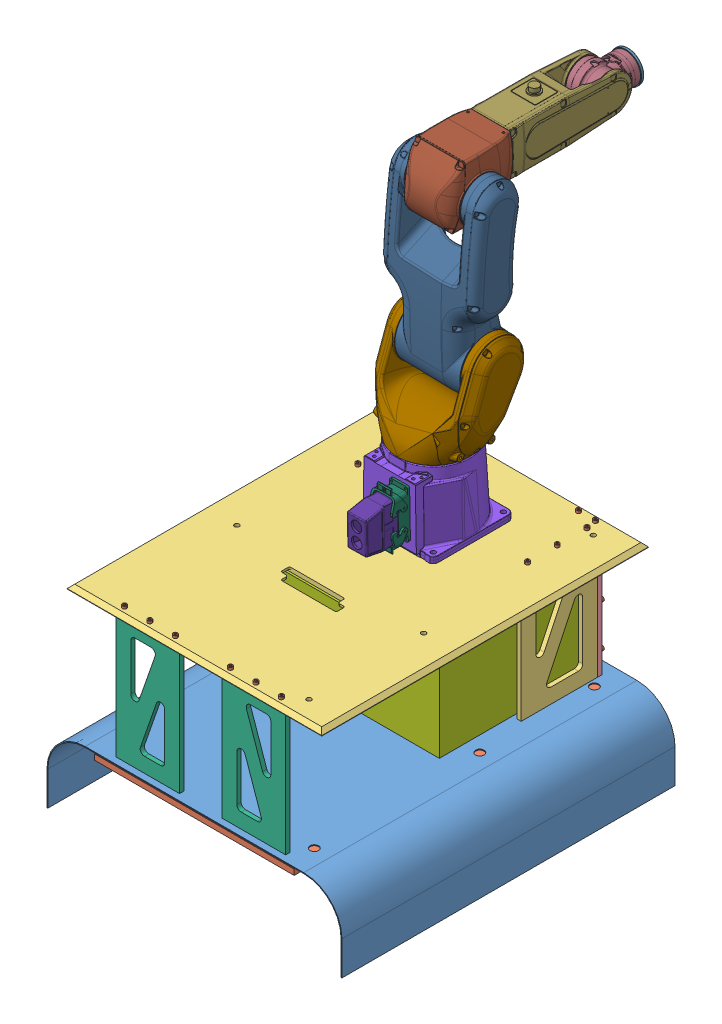
SolidWorks assembly Sistema - Copy, configuration Default. Lengths in mm.
Overall size (695 1239.93 1029.04).
63 component instances, 21 part files, 140 mates.
Components (placement in the parent):
- Curva-1: Curva [Default] at (251.6996 545.3448 205.6123) size (695 170 785)
- Placa Preta-1: Placa Preta [Default] at (486.6996 528.3448 990.6123) x (0 0 -1) z (1 0 0) size (785 15 470)
- L1-1: L1 [Default] at (456.6996 831.4223 235.6123) x (-1 0 0) z (0 0 1) size (60 300 190)
  - PLACA L2-1: PLACA L2 [Default] at (0 286.0775 10) x (0 0 1) z (0 1 0) size (180 10 300)
  - PLACA L1de-1: PLACA L1de [Default] at (0 -13.9225 0) size (60 300 10)
- L2-1: L2 [Default] at (108.7914 900.0363 -121.8565) x (-1 0 0) z (0 0 1) size (60 300 190)
  - PLACA L1d-1: PLACA L1d [Default] at (2.0918 54.6914 357.4688) size (60 300 10)
  - PLACA L2-1: PLACA L2 [Default] at (52.0918 354.6914 367.4688) x (0 0 1) z (0 1 0) size (180 10 300)
- PLACA B-1: PLACA B [Default] at (51.6996 545.3448 965.6123) x (1 0 0) z (0 -1 0) size (150 10 300)
- PLACA B-2: PLACA B [Default] at (451.6996 545.3448 975.6123) x (-1 0 0) z (0 -1 0) size (150 10 300)
- Contro-1: Contro [Default] at (438.6996 548.3448 255.6123) x (-1 0 0) z (0 0 -1) size (370 255 365) (hidden)
- Fanuc - LR Mate-200iD-1: Fanuc - LR Mate-200iD [Default] at (251.6996 856.3448 427.6123) x (0 0 -1) z (1 0 0) size (710.9 759.93 375.98)
  - J1BASE_UNIT-1: J1BASE_UNIT [Default] x (1 0 0) z (0 1 0) size (198 190.35 169.02)
  - J2BASE_UNIT-1: J2BASE_UNIT [Default] at (0 330 0) x (1 0 0) z (0 1 0) size (376.24 375.98 375.98)
  - J2ARM_UNIT-1: J2ARM_UNIT [Default] at (50 330 0) x (1 0 0) z (0 1 0) size (147.39 227.01 447.1)
  - J3HOUSING_UNIT-1: J3HOUSING_UNIT [Default] at (50 660 0) x (1 0 0) z (0 1 0) size (168.21 161.55 138.75)
  - J3ARM_UNIT-1: J3ARM_UNIT [Default] at (48.4 695.0266 0) x (1 0 0) z (0 1 0) size (328.04 104.81 113.9)
  - WRIST_UNIT-1: WRIST_UNIT [Default] at (383.4 695.0266 0) x (1 0 0) z (0 1 0) size (122.73 70.75 85.53)
  - J6RB_COVER-1: J6RB_COVER [Default] at (458.9 695.0266 0) x (0 -1 0) z (-1 0 0) size (74 74 15.5)
  - Harting HAN16B Housing-1: Harting HAN16B Housing [Default] at (-121.8 87.2194 28.1121) x (0 0.999848 -0.017452) z (0 0.017452 0.999848) size (131.63 46.6 57)
  - Harting DD72 Male Insert-1: Harting DD72 Male Insert [Default] at (-121.8 86.9777 28.6164) x (0 -0.999848 0.017452) z (0 0.017452 0.999848) size (84.5 35.16 34)
  - HArting HAN16B Hood-1: HArting HAN16B Hood [Default] at (-142.1 86.9695 28.1151) x (0 -0.999848 0.017452) z (0 -0.017452 -0.999848) size (93.56 76.01 57.01)
  - Harting DD72 Female Insert-1: Harting DD72 Female Insert [Default] at (-142.1 87.0381 28.1569) x (0 0.999848 -0.01745) z (0 0.01745 0.999848) size (84.5 36 34)
  - Fanuc LR-Mate 200iD Bottom Cover Plate-1: Fanuc LR-Mate 200iD Bottom Cover Plate [Default] at (-95.289 2 99.0244) x (0 0 -1) z (-1 0 0) size (165.51 3 180.93)
- socket head cap screw_iso-1: socket head cap screw_iso [ISO 4762 M6 x 20 - 20N] at (451.6996 595.3448 229.6123) x (0 0 1) z (-1 0 0) size (26 10 10)
- socket head cap screw_iso-2: socket head cap screw_iso [ISO 4762 M6 x 20 - 20N] at (451.6996 695.3448 229.6123) x (0 0 1) z (-1 0 0) size (26 10 10)
- socket head cap screw_iso-3: socket head cap screw_iso [ISO 4762 M6 x 20 - 20N] at (451.6996 795.3448 229.6123) x (0 0 1) z (-1 0 0) size (26 10 10)
- socket head cap screw_iso-4: socket head cap screw_iso [ISO 4762 M6 x 20 - 20N] at (51.6996 595.3448 229.6123) x (0 0 1) z (-1 0 0) size (26 10 10)
- socket head cap screw_iso-5: socket head cap screw_iso [ISO 4762 M6 x 20 - 20N] at (51.6996 695.3448 229.6123) x (0 0 1) z (-1 0 0) size (26 10 10)
- socket head cap screw_iso-6: socket head cap screw_iso [ISO 4762 M6 x 20 - 20N] at (51.6996 795.3448 229.6123) x (0 0 1) z (-1 0 0) size (26 10 10)
- socket head cap screw_iso-7: socket head cap screw_iso [ISO 4762 M6 x 30 - 30N] at (436.6996 522.3448 970.6123) x (0 1 0) z (0 0 1) size (36 10 10)
- socket head cap screw_iso-8: socket head cap screw_iso [ISO 4762 M6 x 30 - 30N] at (376.6996 522.3448 970.6123) x (0 1 0) z (0 0 1) size (36 10 10)
- socket head cap screw_iso-9: socket head cap screw_iso [ISO 4762 M6 x 30 - 30N] at (316.6996 522.3448 970.6123) x (0 1 0) z (0 0 1) size (36 10 10)
- socket head cap screw_iso-10: socket head cap screw_iso [ISO 4762 M6 x 30 - 30N] at (186.6996 522.3448 970.6123) x (0 1 0) z (0 0 1) size (36 10 10)
- socket head cap screw_iso-11: socket head cap screw_iso [ISO 4762 M6 x 30 - 30N] at (126.6996 522.3448 970.6123) x (0 1 0) z (0 0 1) size (36 10 10)
- socket head cap screw_iso-12: socket head cap screw_iso [ISO 4762 M6 x 30 - 30N] at (66.6996 522.3448 970.6123) x (0 1 0) z (0 0 1) size (36 10 10)
- socket head cap screw_iso-13: socket head cap screw_iso [ISO 4762 M6 x 30 - 30N] at (51.6996 522.3448 405.6123) x (0 1 0) z (0 0 1) size (36 10 10)
- socket head cap screw_iso-14: socket head cap screw_iso [ISO 4762 M6 x 30 - 30N] at (51.6996 522.3448 335.6123) x (0 1 0) z (0 0 1) size (36 10 10)
- socket head cap screw_iso-15: socket head cap screw_iso [ISO 4762 M6 x 30 - 30N] at (51.6996 522.3448 265.6123) x (0 1 0) z (0 0 1) size (36 10 10)
- socket head cap screw_iso-16: socket head cap screw_iso [ISO 4762 M6 x 30 - 30N] at (96.6996 522.3448 240.6123) x (0 1 0) z (0 0 1) size (36 10 10)
- socket head cap screw_iso-17: socket head cap screw_iso [ISO 4762 M6 x 30 - 30N] at (56.6996 522.3448 240.6123) x (0 1 0) z (0 0 1) size (36 10 10)
- socket head cap screw_iso-19: socket head cap screw_iso [ISO 4762 M6 x 30 - 30N] at (451.6996 522.3448 335.6123) x (0 1 0) z (-0.781824 0 0.623499) size (36 10 10)
- socket head cap screw_iso-20: socket head cap screw_iso [ISO 4762 M6 x 30 - 30N] at (451.6996 522.3448 265.6123) x (0 1 0) z (0 0 1) size (36 10 10)
- socket head cap screw_iso-21: socket head cap screw_iso [ISO 4762 M6 x 30 - 30N] at (446.6996 522.3448 240.6123) x (0 1 0) z (0 0 1) size (36 10 10)
- socket head cap screw_iso-22: socket head cap screw_iso [ISO 4762 M6 x 30 - 30N] at (406.6996 522.3448 240.6123) x (0 1 0) z (0 0 1) size (36 10 10)
- socket head cap screw_iso-25: socket head cap screw_iso [ISO 4762 M6 x 30 - 30N] at (451.6996 522.3448 405.6123) x (0 1 0) z (0 0 1) size (36 10 10)
- Placa Cima Simples-1: Placa Cima Simples [Default] at (-48.3004 845.3448 220.6123) x (0 0 1) z (-1 0 0) size (770 34 600)
- socket head cap screw_iso-27: socket head cap screw_iso [ISO 4762 M6 x 20 - 20N] at (436.6996 861.3448 970.6623) x (0 -1 0) z (0 0 1) size (26 10 10)
- socket head cap screw_iso-28: socket head cap screw_iso [ISO 4762 M6 x 20 - 20N] at (376.6996 861.3448 970.6623) x (0 -1 0) z (0 0 1) size (26 10 10)
- socket head cap screw_iso-29: socket head cap screw_iso [ISO 4762 M6 x 20 - 20N] at (316.6996 861.3448 970.5623) x (0 -1 0) z (0 0 1) size (26 10 10)
- socket head cap screw_iso-30: socket head cap screw_iso [ISO 4762 M6 x 20 - 20N] at (126.6996 861.3448 970.6623) x (0 -1 0) z (0 0 1) size (26 10 10)
- socket head cap screw_iso-31: socket head cap screw_iso [ISO 4762 M6 x 20 - 20N] at (66.6996 861.3448 970.6623) x (0 -1 0) z (0 0 1) size (26 10 10)
- socket head cap screw_iso-32: socket head cap screw_iso [ISO 4762 M6 x 20 - 20N] at (186.6996 861.3448 970.6623) x (0 -1 0) z (0 0 1) size (26 10 10)
- socket head cap screw_iso-34: socket head cap screw_iso [ISO 4762 M6 x 20 - 20N] at (451.6996 861.3448 405.6623) x (0 -1 0) z (0 0 1) size (26 10 10)
- socket head cap screw_iso-35: socket head cap screw_iso [ISO 4762 M6 x 20 - 20N] at (451.6996 861.3448 335.6623) x (0 -1 0) z (0 0 1) size (26 10 10)
- socket head cap screw_iso-36: socket head cap screw_iso [ISO 4762 M6 x 20 - 20N] at (451.6996 861.3448 265.6623) x (0 -1 0) z (0 0 1) size (26 10 10)
- socket head cap screw_iso-37: socket head cap screw_iso [ISO 4762 M6 x 20 - 20N] at (446.6996 861.3448 240.6623) x (0 -1 0) z (0 0 1) size (26 10 10)
- socket head cap screw_iso-38: socket head cap screw_iso [ISO 4762 M6 x 20 - 20N] at (406.6996 861.3448 240.6623) x (0 -1 0) z (0 0 1) size (26 10 10)
- socket head cap screw_iso-39: socket head cap screw_iso [ISO 4762 M6 x 20 - 20N] at (56.6996 861.3448 240.5623) x (0 -1 0) z (0 0 1) size (26 10 10)
- socket head cap screw_iso-40: socket head cap screw_iso [ISO 4762 M6 x 20 - 20N] at (96.6996 861.3448 240.5623) x (0 -1 0) z (0 0 1) size (26 10 10)
- socket head cap screw_iso-41: socket head cap screw_iso [ISO 4762 M6 x 20 - 20N] at (51.6996 861.3448 265.5623) x (0 -1 0) z (0 0 1) size (26 10 10)
- socket head cap screw_iso-42: socket head cap screw_iso [ISO 4762 M6 x 20 - 20N] at (51.6996 861.3448 405.5623) x (0 -1 0) z (0 0 1) size (26 10 10)
- socket head cap screw_iso-43: socket head cap screw_iso [ISO 4762 M6 x 20 - 20N] at (51.6996 861.3448 335.5623) x (0 -1 0) z (0 0 1) size (26 10 10)
Mates (geometry in assembly coordinates):
- Coincident1: coincident anti-aligned: plane of Curva-1 through (-5.8004 543.3448 205.6123) normal (0 -1 0); plane of Placa Preta-1 through (486.6996 543.3448 990.6123) normal (0 1 0)
- Parallel1: parallel anti-aligned: plane of Curva-1 through (599.1996 455.3448 205.6123) normal (1 0 0); plane of Placa Cima Simples-1 through (-48.3004 855.3448 220.6123) normal (-1 0 0)
- Distance1: distance = 300 mm: plane of Curva-1 through (-5.8004 545.3448 205.6123) normal (0 1 0); plane of Placa Cima Simples-1 through (-48.3004 845.3448 220.6123) normal (0 -1 0)
- Coincident4: coincident aligned: plane of Curva-1 through (251.6996 545.3448 205.6123) normal (-1 0 0); plane of Placa Preta-1 through (251.6996 528.3448 990.6123) normal (-1 0 0)
- Coincident25: coincident aligned: plane of Curva-1 through (-95.8004 375.3448 990.6123) normal (0 0 1); plane of Placa Preta-1 through (486.6996 543.3448 990.6123) normal (0 0 1)
- Coincident6: coincident anti-aligned: plane of Curva-1 through (-5.8004 545.3448 205.6123) normal (0 1 0); plane of L1-1/PLACA L2-1 through (446.6996 545.3448 245.6123) normal (0 -1 0)
- Distance2: distance = 30 mm aligned: plane of Placa Preta-1 through (486.6996 543.3448 205.6123) normal (0 0 -1); plane of L1-1/PLACA L1de-1 through (456.6996 845.3448 235.6123) normal (0 0 -1)
- Distance3: distance = 30 mm aligned: plane of L1-1/PLACA L2-1 through (456.6996 545.3448 245.6123) normal (1 0 0); plane of Placa Preta-1 through (486.6996 543.3448 990.6123) normal (1 0 0)
- Coincident9: coincident aligned: plane of L1-1/PLACA L1de-1 through (456.6996 845.3448 235.6123) normal (0 0 -1); plane of L2-1/PLACA L1d-1 through (106.6996 845.3448 235.6123) normal (0 0 -1)
- Coincident10: coincident anti-aligned: plane of Curva-1 through (-5.8004 545.3448 205.6123) normal (0 1 0); plane of L2-1/PLACA L2-1 through (46.6996 545.3448 245.6123) normal (0 -1 0)
- Distance4: distance = 30 mm aligned: plane of L2-1/PLACA L2-1 through (46.6996 545.3448 245.6123) normal (-1 0 0); plane of Placa Preta-1 through (16.6996 543.3448 990.6123) normal (-1 0 0)
- Coincident15: coincident anti-aligned: plane of Curva-1 through (251.6996 545.3448 205.6123) normal (1 0 0); plane of Placa Cima Simples-1 through (251.6996 845.3448 220.6123) normal (-1 0 0)
- Distance5: distance = 370 mm: plane of Placa Cima Simples-1 through (-48.3004 845.3448 605.6123) normal (0 0 -1); plane of L2-1/PLACA L1d-1 through (106.6996 845.3448 235.6123) normal (0 0 -1)
- Coincident16: coincident anti-aligned: plane of Curva-1 through (-5.8004 545.3448 205.6123) normal (0 1 0); plane of PLACA B-1 through (51.6996 545.3448 975.6123) normal (0 -1 0)
- Coincident17: coincident anti-aligned: plane of Curva-1 through (-5.8004 545.3448 205.6123) normal (0 1 0); plane of PLACA B-2 through (451.6996 545.3448 965.6123) normal (0 -1 0)
- Coincident31: coincident aligned: plane of Placa Preta-1 through (41.6996 528.3448 965.6123) normal (0 0 -1); plane of PLACA B-1 through (51.6996 545.3448 965.6123) normal (0 0 -1)
- Coincident21: coincident aligned: plane of PLACA B-1 through (51.6996 545.3448 975.6123) normal (0 0 1); plane of PLACA B-2 through (451.6996 545.3448 975.6123) normal (0 0 1)
- Distance6: distance = 3 mm anti-aligned: plane of Contro-1 through (438.6996 548.3448 255.6123) normal (0 -1 0); plane of Curva-1 through (-5.8004 545.3448 205.6123) normal (0 1 0)
- Distance7: distance = 10 mm anti-aligned: plane of Contro-1 through (438.6996 748.3448 255.6123) normal (0 0 -1); plane of L2-1/PLACA L1d-1 through (106.6996 845.3448 245.6123) normal (0 0 1)
- Distance8: distance = 2 mm anti-aligned: plane of Contro-1 through (108.6996 728.3448 235.6123) normal (-1 0 0); plane of L2-1/PLACA L1d-1 through (106.6996 845.3448 245.6123) normal (1 0 0)
- Coincident26: coincident: plane of Placa Cima Simples-1 through (-48.3004 855.3448 220.6123) normal (0 1 0); plane of Fanuc - LR Mate-200iD-1/Fanuc LR-Mate 200iD Bottom Cover Plate-1 through (338.1874 855.3448 461.1741) normal (0 -1 0)
- Distance10: distance = 95 mm: plane of Placa Cima Simples-1 through (251.6996 845.3448 220.6123) normal (-1 0 0); plane of Fanuc - LR Mate-200iD-1/J1BASE_UNIT-1 through (156.6996 871.3448 522.6123) normal (-1 0 0)
- Distance12: distance = 200 mm: plane of Placa Cima Simples-1 through (325.6996 845.3448 730.6123) normal (0 0 -1); plane of Fanuc - LR Mate-200iD-1/J1BASE_UNIT-1 through (251.6996 856.3448 530.6123) normal (0 0 1)
- Distance13: distance = 5 mm aligned: plane of L2-1/PLACA L2-1 through (46.6996 545.3448 245.6123) normal (-1 0 0); plane of PLACA B-1 through (51.6996 545.3448 975.6123) normal (-1 0 0)
- Distance14: distance = 5 mm aligned: plane of L1-1/PLACA L2-1 through (456.6996 545.3448 245.6123) normal (1 0 0); plane of PLACA B-2 through (451.6996 545.3448 965.6123) normal (1 0 0)
- Concentric2: concentric aligned: cylinder of L1-1/PLACA L1de-1 through (451.6996 595.3448 235.6123) axis (0 0 -1) radius 3.3; cylinder of socket head cap screw_iso-1 through (451.6996 595.3448 197.8623) axis (0 0 -1) radius 5
- Coincident32: coincident anti-aligned: plane of L1-1/PLACA L1de-1 through (456.6996 845.3448 235.6123) normal (0 0 -1); plane of socket head cap screw_iso-1 through (451.6996 600.3448 235.6123) normal (0 0 1)
- Concentric3: concentric aligned: cylinder of L1-1/PLACA L1de-1 through (451.6996 695.3448 235.6123) axis (0 0 -1) radius 3.3; cylinder of socket head cap screw_iso-2 through (451.6996 695.3448 197.8623) axis (0 0 -1) radius 5
- Coincident33: coincident anti-aligned: plane of L1-1/PLACA L1de-1 through (456.6996 845.3448 235.6123) normal (0 0 -1); plane of socket head cap screw_iso-2 through (451.6996 700.3448 235.6123) normal (0 0 1)
- Concentric4: concentric aligned: cylinder of L1-1/PLACA L1de-1 through (451.6996 795.3448 235.6123) axis (0 0 -1) radius 3.3; cylinder of socket head cap screw_iso-3 through (451.6996 795.3448 197.8623) axis (0 0 -1) radius 5
- Coincident34: coincident anti-aligned: plane of L1-1/PLACA L1de-1 through (456.6996 845.3448 235.6123) normal (0 0 -1); plane of socket head cap screw_iso-3 through (451.6996 800.3448 235.6123) normal (0 0 1)
- Concentric5: concentric aligned: cylinder of L2-1/PLACA L1d-1 through (51.6996 595.3448 235.6123) axis (0 0 -1) radius 3.3; cylinder of socket head cap screw_iso-4 through (51.6996 595.3448 197.8623) axis (0 0 -1) radius 5
- Coincident35: coincident anti-aligned: plane of L2-1/PLACA L1d-1 through (106.6996 845.3448 235.6123) normal (0 0 -1); plane of socket head cap screw_iso-4 through (51.6996 600.3448 235.6123) normal (0 0 1)
- Concentric6: concentric aligned: cylinder of L2-1/PLACA L1d-1 through (51.6996 695.3448 235.6123) axis (0 0 -1) radius 3.3; cylinder of socket head cap screw_iso-5 through (51.6996 695.3448 197.8623) axis (0 0 -1) radius 5
- Coincident36: coincident anti-aligned: plane of L2-1/PLACA L1d-1 through (106.6996 845.3448 235.6123) normal (0 0 -1); plane of socket head cap screw_iso-5 through (51.6996 700.3448 235.6123) normal (0 0 1)
- Concentric7: concentric aligned: cylinder of L2-1/PLACA L1d-1 through (51.6996 795.3448 235.6123) axis (0 0 -1) radius 3.3; cylinder of socket head cap screw_iso-6 through (51.6996 795.3448 197.8623) axis (0 0 -1) radius 5
- Coincident37: coincident anti-aligned: plane of L2-1/PLACA L1d-1 through (106.6996 845.3448 235.6123) normal (0 0 -1); plane of socket head cap screw_iso-6 through (51.6996 800.3448 235.6123) normal (0 0 1)
- Concentric8: concentric aligned: cylinder of Placa Preta-1 through (436.6996 528.3448 970.6123) axis (0 -1 0) radius 3.3; cylinder of socket head cap screw_iso-7 through (436.6996 490.5948 970.6123) axis (0 -1 0) radius 5
- Coincident38: coincident anti-aligned: plane of Placa Preta-1 through (486.6996 528.3448 990.6123) normal (0 -1 0); plane of socket head cap screw_iso-7 through (431.6996 528.3448 970.6123) normal (0 1 0)
- Concentric9: concentric aligned: cylinder of Placa Preta-1 through (376.6996 528.3448 970.6123) axis (0 -1 0) radius 3.3; cylinder of socket head cap screw_iso-8 through (376.6996 490.5948 970.6123) axis (0 -1 0) radius 5
- Coincident39: coincident anti-aligned: plane of Placa Preta-1 through (486.6996 528.3448 990.6123) normal (0 -1 0); plane of socket head cap screw_iso-8 through (371.6996 528.3448 970.6123) normal (0 1 0)
- Concentric10: concentric aligned: cylinder of Placa Preta-1 through (316.6996 528.3448 970.6123) axis (0 -1 0) radius 3.3; cylinder of socket head cap screw_iso-9 through (316.6996 490.5948 970.6123) axis (0 -1 0) radius 5
- Coincident40: coincident anti-aligned: plane of Placa Preta-1 through (486.6996 528.3448 990.6123) normal (0 -1 0); plane of socket head cap screw_iso-9 through (311.6996 528.3448 970.6123) normal (0 1 0)
- Concentric11: concentric aligned: cylinder of Placa Preta-1 through (186.6996 528.3448 970.6123) axis (0 -1 0) radius 3.3; cylinder of socket head cap screw_iso-10 through (186.6996 490.5948 970.6123) axis (0 -1 0) radius 5
- Coincident41: coincident anti-aligned: plane of Placa Preta-1 through (486.6996 528.3448 990.6123) normal (0 -1 0); plane of socket head cap screw_iso-10 through (181.6996 528.3448 970.6123) normal (0 1 0)
- Concentric12: concentric aligned: cylinder of Placa Preta-1 through (126.6996 528.3448 970.6123) axis (0 -1 0) radius 3.3; cylinder of socket head cap screw_iso-11 through (126.6996 490.5948 970.6123) axis (0 -1 0) radius 5
- Coincident42: coincident anti-aligned: plane of Placa Preta-1 through (486.6996 528.3448 990.6123) normal (0 -1 0); plane of socket head cap screw_iso-11 through (121.6996 528.3448 970.6123) normal (0 1 0)
- Concentric13: concentric aligned: cylinder of Placa Preta-1 through (66.6996 528.3448 970.6123) axis (0 -1 0) radius 3.3; cylinder of socket head cap screw_iso-12 through (66.6996 490.5948 970.6123) axis (0 -1 0) radius 5
- Coincident43: coincident anti-aligned: plane of Placa Preta-1 through (486.6996 528.3448 990.6123) normal (0 -1 0); plane of socket head cap screw_iso-12 through (61.6996 528.3448 970.6123) normal (0 1 0)
- Concentric14: concentric aligned: cylinder of Placa Preta-1 through (51.6996 528.3448 405.6123) axis (0 -1 0) radius 3.3; cylinder of socket head cap screw_iso-13 through (51.6996 490.5948 405.6123) axis (0 -1 0) radius 5
- Coincident44: coincident anti-aligned: plane of Placa Preta-1 through (486.6996 528.3448 990.6123) normal (0 -1 0); plane of socket head cap screw_iso-13 through (46.6996 528.3448 405.6123) normal (0 1 0)
- Concentric15: concentric aligned: cylinder of Placa Preta-1 through (51.6996 528.3448 335.6123) axis (0 -1 0) radius 3.3; cylinder of socket head cap screw_iso-14 through (51.6996 490.5948 335.6123) axis (0 -1 0) radius 5
- Coincident45: coincident anti-aligned: plane of Placa Preta-1 through (486.6996 528.3448 990.6123) normal (0 -1 0); plane of socket head cap screw_iso-14 through (46.6996 528.3448 335.6123) normal (0 1 0)
- Concentric16: concentric aligned: cylinder of Placa Preta-1 through (51.6996 528.3448 265.6123) axis (0 -1 0) radius 3.3; cylinder of socket head cap screw_iso-15 through (51.6996 490.5948 265.6123) axis (0 -1 0) radius 5
- Coincident46: coincident anti-aligned: plane of Placa Preta-1 through (486.6996 528.3448 990.6123) normal (0 -1 0); plane of socket head cap screw_iso-15 through (46.6996 528.3448 265.6123) normal (0 1 0)
- Concentric17: concentric aligned: cylinder of Placa Preta-1 through (96.6996 528.3448 240.6123) axis (0 -1 0) radius 3.3; cylinder of socket head cap screw_iso-16 through (96.6996 490.5948 240.6123) axis (0 -1 0) radius 5
- Coincident47: coincident anti-aligned: plane of Placa Preta-1 through (486.6996 528.3448 990.6123) normal (0 -1 0); plane of socket head cap screw_iso-16 through (91.6996 528.3448 240.6123) normal (0 1 0)
- Concentric18: concentric aligned: cylinder of Placa Preta-1 through (56.6996 528.3448 240.6123) axis (0 -1 0) radius 3.3; cylinder of socket head cap screw_iso-17 through (56.6996 490.5948 240.6123) axis (0 -1 0) radius 5
- Coincident48: coincident anti-aligned: plane of Placa Preta-1 through (486.6996 528.3448 990.6123) normal (0 -1 0); plane of socket head cap screw_iso-17 through (51.6996 528.3448 240.6123) normal (0 1 0)
- Concentric19: concentric aligned: cylinder of Placa Preta-1 through (451.6996 528.3448 405.6123) axis (0 -1 0) radius 3.3; cylinder of ? through (451.6996 439.3427 405.6123) axis (0 -1 0) radius 5
- Concentric20: concentric aligned: cylinder of Placa Preta-1 through (451.6996 528.3448 335.6123) axis (0 -1 0) radius 3.3; cylinder of socket head cap screw_iso-19 through (451.6996 490.5948 335.6123) axis (0 -1 0) radius 5
- Coincident49: coincident anti-aligned: plane of Placa Preta-1 through (486.6996 528.3448 990.6123) normal (0 -1 0); plane of socket head cap screw_iso-19 through (448.5821 528.3448 331.7032) normal (0 1 0)
- Concentric21: concentric aligned: cylinder of Placa Preta-1 through (451.6996 528.3448 265.6123) axis (0 -1 0) radius 3.3; cylinder of socket head cap screw_iso-20 through (451.6996 490.5948 265.6123) axis (0 -1 0) radius 5
- Coincident50: coincident anti-aligned: plane of Placa Preta-1 through (486.6996 528.3448 990.6123) normal (0 -1 0); plane of socket head cap screw_iso-20 through (446.6996 528.3448 265.6123) normal (0 1 0)
- Concentric22: concentric aligned: cylinder of Placa Preta-1 through (446.6996 528.3448 240.6123) axis (0 -1 0) radius 3.3; cylinder of socket head cap screw_iso-21 through (446.6996 490.5948 240.6123) axis (0 -1 0) radius 5
- Coincident51: coincident anti-aligned: plane of Placa Preta-1 through (486.6996 528.3448 990.6123) normal (0 -1 0); plane of socket head cap screw_iso-21 through (441.6996 528.3448 240.6123) normal (0 1 0)
- Concentric23: concentric aligned: cylinder of Placa Preta-1 through (406.6996 528.3448 240.6123) axis (0 -1 0) radius 3.3; cylinder of socket head cap screw_iso-22 through (406.6996 490.5948 240.6123) axis (0 -1 0) radius 5
- Coincident52: coincident anti-aligned: plane of Placa Preta-1 through (486.6996 528.3448 990.6123) normal (0 -1 0); plane of socket head cap screw_iso-22 through (401.6996 528.3448 240.6123) normal (0 1 0)
- Concentric24: concentric aligned: cylinder of Placa Preta-1 through (451.6996 528.3448 405.6123) axis (0 -1 0) radius 3.3; cylinder of socket head cap screw_iso-25 through (451.6996 490.5948 405.6123) axis (0 -1 0) radius 5
- Coincident53: coincident anti-aligned: plane of Placa Preta-1 through (486.6996 528.3448 990.6123) normal (0 -1 0); plane of socket head cap screw_iso-25 through (446.6996 528.3448 405.6123) normal (0 1 0)
- Concentric27: concentric aligned: cylinder of L2-1/PLACA L1d-1 through (56.6996 845.3448 240.6123) axis (0 1 0) radius 2.5; cone of ? through (56.6996 824.6184 240.6123) axis (0 1 0)
- Coincident54: coincident: cone of Placa Cima Simples-1 through (56.6996 855.3448 240.6123) axis (0 -1 0); cone of ? through (56.6996 843.3748 240.6123) axis (0 1 0)
- Concentric28: concentric: cylinder of Placa Cima Simples-1 through (56.6996 855.3448 240.6123) axis (0 1 0) radius 3.3; cylinder of ? through (56.6996 855.7648 240.6123) axis (0 1 0) radius 3
- Coincident55: coincident: cone of Placa Cima Simples-1 through (56.6996 855.3448 240.6123) axis (0 -1 0); cone of ? through (56.6996 854.7148 240.6123) axis (0 -1 0)
- Concentric29: concentric: circle of Placa Cima Simples-1; cylinder of ? through (96.6996 855.7648 240.6123) axis (0 1 0) radius 3
- Coincident56: coincident: cone of Placa Cima Simples-1 through (96.6996 855.3448 240.6123) axis (0 -1 0); cone of ? through (96.6996 854.7148 240.6123) axis (0 -1 0)
- Concentric30: concentric: cylinder of Placa Cima Simples-1 through (51.6996 855.3448 265.6123) axis (0 1 0) radius 3.3; cylinder of ? through (51.6996 855.7648 265.6123) axis (0 1 0) radius 3
- Coincident57: coincident: cone of Placa Cima Simples-1 through (51.6996 855.3448 265.6123) axis (0 -1 0); cone of ? through (51.6996 854.7148 265.6123) axis (0 -1 0)
- Concentric32: concentric: cylinder of Placa Cima Simples-1 through (51.6996 855.3448 335.6123) axis (0 1 0) radius 3.3; cylinder of ? through (51.6996 855.7648 335.6123) axis (0 1 0) radius 3
- Coincident58: coincident: cone of Placa Cima Simples-1 through (51.6996 855.3448 335.6123) axis (0 -1 0); cone of ? through (51.6996 854.7148 335.6123) axis (0 -1 0)
- Concentric33: concentric: circle of Placa Cima Simples-1; cylinder of ? through (51.6996 855.7648 405.6123) axis (0 1 0) radius 3
- Coincident59: coincident: cone of Placa Cima Simples-1 through (51.6996 855.3448 405.6123) axis (0 -1 0); cone of ? through (51.6996 854.7148 405.6123) axis (0 -1 0)
- Concentric34: concentric: cylinder of Placa Cima Simples-1 through (66.6996 855.3448 970.6123) axis (0 1 0) radius 3.3; cylinder of ? through (66.6996 855.7648 970.6123) axis (0 1 0) radius 3
- Concentric35: concentric: circle of Placa Cima Simples-1; cylinder of ? through (126.6996 855.7648 970.6123) axis (0 1 0) radius 3
- Concentric36: concentric: circle of Placa Cima Simples-1; cylinder of ? through (186.6996 855.7648 970.6123) axis (0 1 0) radius 3
- Coincident60: coincident: cone of Placa Cima Simples-1 through (66.6996 855.3448 970.6123) axis (0 -1 0); cone of ? through (66.6996 854.7148 970.6123) axis (0 -1 0)
- Coincident61: coincident: cone of Placa Cima Simples-1 through (126.6996 855.3448 970.6123) axis (0 -1 0); cone of ? through (126.6996 854.7148 970.6123) axis (0 -1 0)
- Coincident62: coincident: cone of Placa Cima Simples-1 through (186.6996 855.3448 970.6123) axis (0 -1 0); cone of ? through (186.6996 854.7148 970.6123) axis (0 -1 0)
- Concentric37: concentric: cylinder of Placa Cima Simples-1 through (436.6996 855.3448 970.6123) axis (0 1 0) radius 3.3; cylinder of ? through (436.6996 855.7648 970.6123) axis (0 1 0) radius 3
- Concentric38: concentric: cylinder of Placa Cima Simples-1 through (376.6996 855.3448 970.6123) axis (0 1 0) radius 3.3; cylinder of ? through (376.6996 855.7648 970.6123) axis (0 1 0) radius 3
- Concentric39: concentric: cylinder of Placa Cima Simples-1 through (316.6996 855.3448 970.6123) axis (0 1 0) radius 3.3; cylinder of ? through (316.6996 855.7648 970.6123) axis (0 1 0) radius 3
- Coincident63: coincident: cone of Placa Cima Simples-1 through (436.6996 855.3448 970.6123) axis (0 -1 0); cone of ? through (436.6996 854.7148 970.6123) axis (0 -1 0)
- Coincident64: coincident: cone of Placa Cima Simples-1 through (376.6996 855.3448 970.6123) axis (0 -1 0); cone of ? through (376.6996 854.7148 970.6123) axis (0 -1 0)
- Coincident66: coincident: cone of Placa Cima Simples-1 through (316.6996 855.3448 970.6123) axis (0 -1 0); cone of ? through (316.6996 854.7148 970.6123) axis (0 -1 0)
- Concentric40: concentric: circle of Placa Cima Simples-1; cylinder of ? through (406.6996 855.7648 240.6123) axis (0 1 0) radius 3
- Concentric41: concentric: cylinder of Placa Cima Simples-1 through (446.6996 855.3448 240.6123) axis (0 1 0) radius 3.3; cylinder of ? through (446.6996 855.7648 240.6123) axis (0 1 0) radius 3
- Concentric42: concentric: cylinder of Placa Cima Simples-1 through (451.6996 855.3448 265.6123) axis (0 1 0) radius 3.3; cylinder of ? through (451.6996 855.7648 265.6123) axis (0 1 0) radius 3
- Concentric43: concentric: cylinder of Placa Cima Simples-1 through (451.6996 855.3448 335.6123) axis (0 1 0) radius 3.3; cylinder of ? through (451.6996 855.7648 335.6123) axis (0 1 0) radius 3
- Concentric44: concentric: cylinder of Placa Cima Simples-1 through (451.6996 855.3448 405.6123) axis (0 1 0) radius 3.3; cylinder of ? through (451.6996 855.7648 405.6123) axis (0 1 0) radius 3
- Coincident67: coincident aligned: cone of Placa Cima Simples-1 through (406.6996 855.3448 240.6123) axis (0 -1 0); cone of ? through (406.6996 854.7148 240.6123) axis (0 -1 0)
- Coincident68: coincident aligned: cone of Placa Cima Simples-1 through (446.6996 855.3448 240.6123) axis (0 -1 0); cone of ? through (446.6996 854.7148 240.6123) axis (0 -1 0)
- Coincident69: coincident aligned: cone of Placa Cima Simples-1 through (451.6996 855.3448 265.6123) axis (0 -1 0); cone of ? through (451.6996 854.7148 265.6123) axis (0 -1 0)
- Coincident70: coincident aligned: cone of Placa Cima Simples-1 through (451.6996 855.3448 335.6123) axis (0 -1 0); cone of ? through (451.6996 854.7148 335.6123) axis (0 -1 0)
- Coincident71: coincident aligned: cone of Placa Cima Simples-1 through (451.6996 855.3448 405.6123) axis (0 -1 0); cone of ? through (451.6996 854.7148 405.6123) axis (0 -1 0)
- Coincident72: coincident aligned: plane of Placa Preta-1 through (251.6996 528.3448 990.6123) normal (-1 0 0); plane of Placa Cima Simples-1 through (251.6996 845.3448 220.6123) normal (-1 0 0)
- Coincident73: coincident anti-aligned: plane of L1-1/PLACA L2-1 through (446.6996 845.3448 245.6123) normal (0 1 0); plane of Placa Cima Simples-1 through (-48.3004 845.3448 220.6123) normal (0 -1 0)
- Distance15: distance = 15 mm aligned: plane of Placa Cima Simples-1 through (-48.3004 855.3448 220.6123) normal (0 0 -1); plane of L2-1/PLACA L1d-1 through (106.6996 845.3448 235.6123) normal (0 0 -1)
- Concentric47: concentric aligned: cylinder of Placa Cima Simples-1 through (436.6996 855.3448 970.6623) axis (0 1 0) radius 3.25; cylinder of socket head cap screw_iso-27 through (436.6996 893.0948 970.6623) axis (0 1 0) radius 5
- Coincident75: coincident anti-aligned: plane of Placa Cima Simples-1 through (-48.3004 855.3448 220.6123) normal (0 1 0); plane of socket head cap screw_iso-27 through (441.6996 855.3448 970.6623) normal (0 -1 0)
- Concentric48: concentric aligned: cylinder of Placa Cima Simples-1 through (376.6996 855.3448 970.6623) axis (0 1 0) radius 3.25; cylinder of socket head cap screw_iso-28 through (376.6996 893.0948 970.6623) axis (0 1 0) radius 5
- Coincident76: coincident anti-aligned: plane of Placa Cima Simples-1 through (-48.3004 855.3448 220.6123) normal (0 1 0); plane of socket head cap screw_iso-28 through (381.6996 855.3448 970.6623) normal (0 -1 0)
- Concentric49: concentric aligned: cylinder of Placa Cima Simples-1 through (316.6996 855.3448 970.5623) axis (0 1 0) radius 3.25; cylinder of socket head cap screw_iso-29 through (316.6996 893.0948 970.5623) axis (0 1 0) radius 5
- Coincident77: coincident anti-aligned: plane of Placa Cima Simples-1 through (-48.3004 855.3448 220.6123) normal (0 1 0); plane of socket head cap screw_iso-29 through (321.6996 855.3448 970.5623) normal (0 -1 0)
- Concentric50: concentric aligned: cylinder of Placa Cima Simples-1 through (126.6996 855.3448 970.6623) axis (0 1 0) radius 3.25; cylinder of socket head cap screw_iso-30 through (126.6996 893.0948 970.6623) axis (0 1 0) radius 5
- Coincident78: coincident anti-aligned: plane of Placa Cima Simples-1 through (-48.3004 855.3448 220.6123) normal (0 1 0); plane of socket head cap screw_iso-30 through (131.6996 855.3448 970.6623) normal (0 -1 0)
- Concentric51: concentric aligned: cylinder of Placa Cima Simples-1 through (66.6996 855.3448 970.6623) axis (0 1 0) radius 3.25; cylinder of socket head cap screw_iso-31 through (66.6996 893.0948 970.6623) axis (0 1 0) radius 5
- Coincident79: coincident anti-aligned: plane of Placa Cima Simples-1 through (-48.3004 855.3448 220.6123) normal (0 1 0); plane of socket head cap screw_iso-31 through (71.6996 855.3448 970.6623) normal (0 -1 0)
- Concentric52: concentric aligned: cylinder of Placa Cima Simples-1 through (186.6996 855.3448 970.6623) axis (0 1 0) radius 3.25; cylinder of socket head cap screw_iso-32 through (186.6996 893.0948 970.6623) axis (0 1 0) radius 5
- Coincident80: coincident anti-aligned: plane of Placa Cima Simples-1 through (-48.3004 855.3448 220.6123) normal (0 1 0); plane of socket head cap screw_iso-32 through (191.6996 855.3448 970.6623) normal (0 -1 0)
- Concentric53: concentric: cylinder of Placa Cima Simples-1 through (451.6996 855.3448 405.5623) axis (0 1 0) radius 3.25; cylinder of ? through (451.6996 900.8775 405.5623) axis (0 1 0) radius 5
- Concentric54: concentric aligned: cylinder of Placa Cima Simples-1 through (451.6996 855.3448 405.6623) axis (0 1 0) radius 3.25; cylinder of socket head cap screw_iso-34 through (451.6996 893.0948 405.6623) axis (0 1 0) radius 5
- Coincident81: coincident anti-aligned: plane of Placa Cima Simples-1 through (-48.3004 855.3448 220.6123) normal (0 1 0); plane of socket head cap screw_iso-34 through (456.6996 855.3448 405.6623) normal (0 -1 0)
- Concentric55: concentric aligned: cylinder of Placa Cima Simples-1 through (451.6996 855.3448 335.6623) axis (0 1 0) radius 3.25; cylinder of socket head cap screw_iso-35 through (451.6996 893.0948 335.6623) axis (0 1 0) radius 5
- Coincident82: coincident anti-aligned: plane of Placa Cima Simples-1 through (-48.3004 855.3448 220.6123) normal (0 1 0); plane of socket head cap screw_iso-35 through (456.6996 855.3448 335.6623) normal (0 -1 0)
- Concentric56: concentric aligned: cylinder of Placa Cima Simples-1 through (451.6996 855.3448 265.6623) axis (0 1 0) radius 3.25; cylinder of socket head cap screw_iso-36 through (451.6996 893.0948 265.6623) axis (0 1 0) radius 5
- Coincident83: coincident anti-aligned: plane of Placa Cima Simples-1 through (-48.3004 855.3448 220.6123) normal (0 1 0); plane of socket head cap screw_iso-36 through (456.6996 855.3448 265.6623) normal (0 -1 0)
- Concentric57: concentric aligned: cylinder of Placa Cima Simples-1 through (446.6996 855.3448 240.6623) axis (0 1 0) radius 3.25; cylinder of socket head cap screw_iso-37 through (446.6996 893.0948 240.6623) axis (0 1 0) radius 5
- Coincident84: coincident anti-aligned: plane of Placa Cima Simples-1 through (-48.3004 855.3448 220.6123) normal (0 1 0); plane of socket head cap screw_iso-37 through (451.6996 855.3448 240.6623) normal (0 -1 0)
- Concentric58: concentric aligned: cylinder of Placa Cima Simples-1 through (406.6996 855.3448 240.6623) axis (0 1 0) radius 3.25; cylinder of socket head cap screw_iso-38 through (406.6996 893.0948 240.6623) axis (0 1 0) radius 5
- Coincident85: coincident anti-aligned: plane of Placa Cima Simples-1 through (-48.3004 855.3448 220.6123) normal (0 1 0); plane of socket head cap screw_iso-38 through (411.6996 855.3448 240.6623) normal (0 -1 0)
- Concentric59: concentric aligned: cylinder of Placa Cima Simples-1 through (56.6996 855.3448 240.5623) axis (0 1 0) radius 3.25; cylinder of socket head cap screw_iso-39 through (56.6996 893.0948 240.5623) axis (0 1 0) radius 5
- Coincident86: coincident anti-aligned: plane of Placa Cima Simples-1 through (-48.3004 855.3448 220.6123) normal (0 1 0); plane of socket head cap screw_iso-39 through (61.6996 855.3448 240.5623) normal (0 -1 0)
- Concentric60: concentric aligned: cylinder of Placa Cima Simples-1 through (96.6996 855.3448 240.5623) axis (0 1 0) radius 3.25; cylinder of socket head cap screw_iso-40 through (96.6996 893.0948 240.5623) axis (0 1 0) radius 5
- Coincident87: coincident anti-aligned: plane of Placa Cima Simples-1 through (-48.3004 855.3448 220.6123) normal (0 1 0); plane of socket head cap screw_iso-40 through (101.6996 855.3448 240.5623) normal (0 -1 0)
- Concentric61: concentric aligned: cylinder of Placa Cima Simples-1 through (51.6996 855.3448 265.5623) axis (0 1 0) radius 3.25; cylinder of socket head cap screw_iso-41 through (51.6996 893.0948 265.5623) axis (0 1 0) radius 5
- Coincident88: coincident anti-aligned: plane of Placa Cima Simples-1 through (-48.3004 855.3448 220.6123) normal (0 1 0); plane of socket head cap screw_iso-41 through (56.6996 855.3448 265.5623) normal (0 -1 0)
- Concentric62: concentric aligned: cylinder of Placa Cima Simples-1 through (51.6996 855.3448 405.5623) axis (0 1 0) radius 3.25; cylinder of socket head cap screw_iso-42 through (51.6996 893.0948 405.5623) axis (0 1 0) radius 5
- Coincident89: coincident anti-aligned: plane of Placa Cima Simples-1 through (-48.3004 855.3448 220.6123) normal (0 1 0); plane of socket head cap screw_iso-42 through (56.6996 855.3448 405.5623) normal (0 -1 0)
- Concentric63: concentric aligned: cylinder of Placa Cima Simples-1 through (51.6996 855.3448 335.5623) axis (0 1 0) radius 3.25; cylinder of socket head cap screw_iso-43 through (51.6996 893.0948 335.5623) axis (0 1 0) radius 5
- Coincident90: coincident anti-aligned: plane of Placa Cima Simples-1 through (-48.3004 855.3448 220.6123) normal (0 1 0); plane of socket head cap screw_iso-43 through (56.6996 855.3448 335.5623) normal (0 -1 0)
